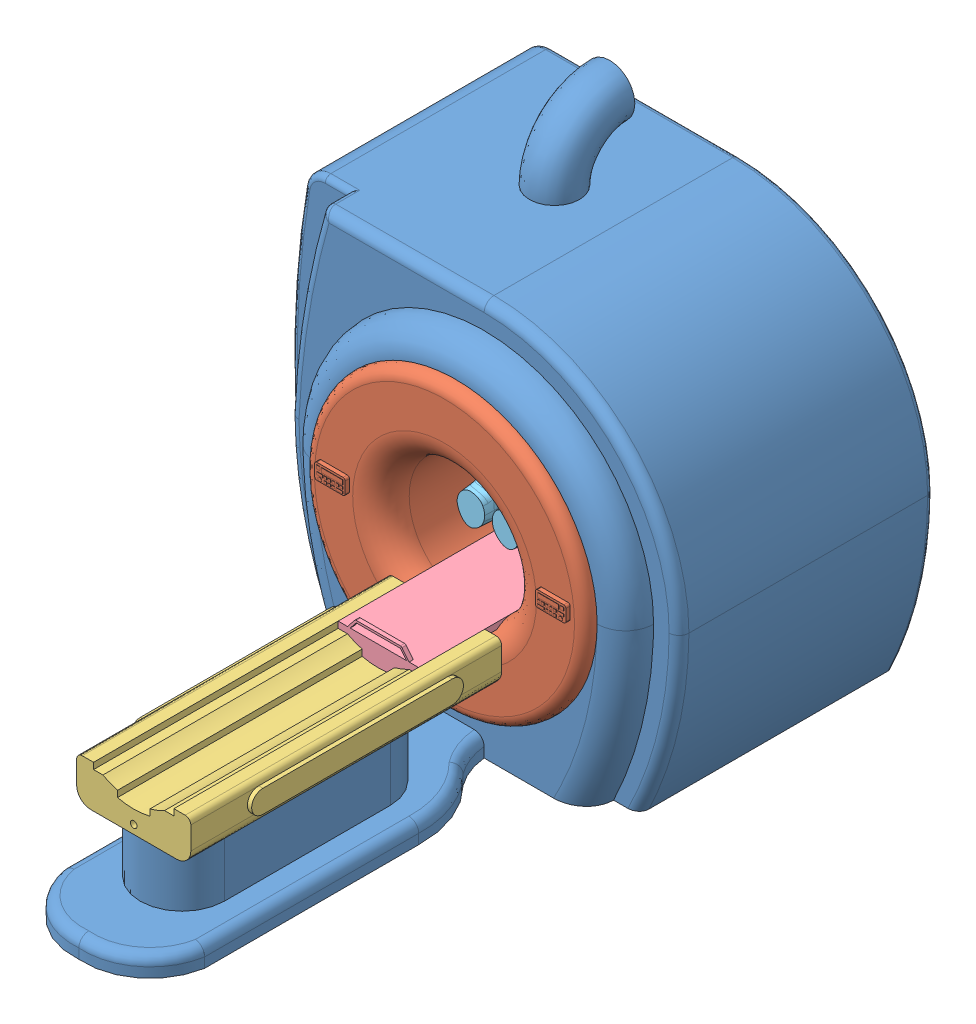
SolidWorks assembly BODYdetectorMRI, configuration Default. Lengths in mm.
Overall size (2298.25 2472.53 3646.55).
34 component instances, 9 part files, 9 mates.
Components (placement in the parent):
- MRI scanner-1: MRI scanner [Default] at (661.8458 1614.7998 1684.1916) size (2298.25 2472.53 3646.55)
  - Base Frame-1: Base Frame [Default] at (215.0742 187.8159 122.1083) size (2298.25 2472.53 3646.55)
  - Center Part-1: Center Part [Default] at (370.4063 184.7421 93.4615) size (1560 1560 1647.36)
  - Bed Base-1: Bed Base [Default] at (341.9747 -206.076 1751.6096) size (677.53 234 1716)
- Moving Bed-1: Moving Bed [Default] at (1003.8204 1488.5238 2088.1633) size (443.53 166.13 1716)
- BODYdetector3-1: BODYdetector3 [Default] at (1343.6656 1349.2154 2674.8103) x (-1 0 0) z (0 0 -1) size (637.83 509.15 817.55)
  - woman body-1: woman body [Default] at (325.4407 484.4544 221.086) size (637.83 301.02 817.55)
  - Detector1n3_3-1: Detector1n3_3 [Default] at (49.8582 665.158 553.2219) x (1 0 0) z (0 -1 0) size (495.24 340.33 231)
    - Detector1n2_changed-1: Detector1n2_changed [Default] at (214.6875 32.8122 259.0633) size (495.24 340.33 200.99)
      - top_bottomDetector2-1: top_bottomDetector2 [Default] at (5.3043 60.2155 74.3483) size (141 32 149.74)
      - CshapedDetector2-1: CshapedDetector2 [Default] at (104.3454 -76.5763 -85.899) x (0.951057 0.309017 0) z (0 0 1) size (177.89 270.84 200)
        - 1Detector-2: 1Detector [Default] at (173.0714 153.2337 184.2598) x (0.809017 0.587785 0) z (0 0 1) size (71 32 200)
        - 1Detector-4: 1Detector [Default] at (223.2683 222.3237 184.2598) x (0.309017 0.951057 0) z (0 0 1) size (71 32 200)
        - 1Detector-5: 1Detector [Default] at (223.2683 307.7237 184.2598) x (-0.309017 0.951057 0) z (0 0 1) size (71 32 200)
        - 1Detector_3modules-1: 1Detector_3modules [Default] at (91.8512 126.8436 209.2598) size (71 32 150)
        - 1Detector_3modules-2: 1Detector_3modules [Default] at (173.0714 376.8138 209.2598) x (-0.809017 0.587785 0) z (0 0 1) size (71 32 150)
      - CshapedDetector2-2: CshapedDetector2 [Default] at (-23.7368 484.2959 -85.899) x (-0.951057 -0.309017 0) z (0 0 1) size (177.89 270.84 200)
        - 1Detector-2: 1Detector [Default] at (173.0714 153.2337 184.2598) x (0.809017 0.587785 0) z (0 0 1) size (71 32 200)
        - 1Detector-4: 1Detector [Default] at (223.2683 222.3237 184.2598) x (0.309017 0.951057 0) z (0 0 1) size (71 32 200)
        - 1Detector-5: 1Detector [Default] at (223.2683 307.7237 184.2598) x (-0.309017 0.951057 0) z (0 0 1) size (71 32 200)
        - 1Detector_3modules-1: 1Detector_3modules [Default] at (91.8512 126.8436 209.2598) size (71 32 150)
        - 1Detector_3modules-2: 1Detector_3modules [Default] at (173.0714 376.8138 209.2598) x (-0.809017 0.587785 0) z (0 0 1) size (71 32 150)
      - top_bottomDetector2-2: top_bottomDetector2 [Default] at (75.3043 347.5042 74.3483) x (-1 0 0) z (0 0 1) size (141 32 149.74)
    - Detector3-1: Detector3 [Default] at (255.9219 239.5761 488.4241) x (0 -1 0) z (1 0 0) size (239.5 31 350)
  - Detector_posterial2-1: Detector_posterial2 [Default] at (218.3959 771.2045 927.1336) x (1 0 0) z (0 0 -1) size (410.4 279.65 200.24)
    - 1Detector-1: 1Detector [Default] at (83.9721 85.3161 150.6758) size (71 32 200)
    - 1Detector-2: 1Detector [Default] at (152.9721 85.3161 150.6758) size (71 32 200)
    - 1Detector-3: 1Detector [Default] at (14.9721 85.3161 150.6758) size (71 32 200)
    - 1Detector-4: 1Detector [Default] at (-66.1879 111.2254 150.6758) x (0.815027 -0.579423 0) z (0 0 1) size (71 32 200)
    - 1Detector-5: 1Detector [Default] at (234.132 111.2254 150.6758) x (0.815027 0.579423 0) z (0 0 1) size (71 32 200)
    - 1Detector_3modules-1: 1Detector_3modules [Default] at (-113.8805 184.8905 175.6758) x (0.19509 -0.980785 0) z (0 0 1) size (71 32 150)
    - 1Detector_3modules-2: 1Detector_3modules [Default] at (281.8247 184.8905 175.6758) x (0.19509 0.980785 0) z (0 0 1) size (71 32 150)
    - top_bottomDetector2-1: top_bottomDetector2 [Default] at (289.1701 259.4705 125.9183) x (0 1 0) z (0 0 1) size (141 32 149.74)
    - top_bottomDetector2-2: top_bottomDetector2 [Default] at (-121.226 329.4705 125.9183) x (0 -1 0) z (0 0 1) size (141 32 149.74)
Mates (geometry in assembly coordinates):
- Coincident1: coincident aligned: line of MRI scanner-1/Bed Base-1 through (810.4856 1491.0005 4405.104) axis (0 0 -1); line of Moving Bed-1 through (810.4856 1491.0005 3054.7931) axis (0 0 -1)
- Parallel1: parallel anti-aligned: plane of MRI scanner-1/Bed Base-1 through (810.4856 1491.0005 4405.104) normal (0 1 0); plane of Moving Bed-1 through (810.4856 1491.0005 3054.7931) normal (0 -1 0)
- Coincident4: coincident anti-aligned: plane of Moving Bed-1 through (810.4856 1525.9494 3298.5256) normal (0 1 0); plane of ? through (940.4185 1525.9494 1968.3934) normal (0 -1 0)
- Distance2: distance = 228.6 mm: line of Moving Bed-1 through (1254.0185 1525.9494 3298.5256) axis (0 0 -1); line of ? through (1025.4185 1525.9494 2043.3934) axis (0 0 -1)
- Distance3: distance = 310.8678 mm: line of ? through (1206.7786 1525.9494 1893.3934) axis (-1 0 0); line of Moving Bed-1 through (1254.0185 1525.9494 1582.5256) axis (-1 0 0)
- Parallel2: parallel aligned: line of Moving Bed-1 through (1254.0185 1525.9494 3054.7931) axis (0 0 -1); line of BODYdetector3-1/Detector1n3_3-1/Detector3-1 through (1212.8855 1530.9494 1992.0123) axis (0 0 -1)
- Coincident6: coincident anti-aligned: plane of Moving Bed-1 through (810.4856 1525.9494 3054.7931) normal (0 1 0); plane of BODYdetector3-1/Detector1n3_3-1/Detector3-1 through (1037.8855 1525.9494 1882.0123) normal (0 -1 0)
- Distance4: distance = 41.1329 mm aligned: plane of BODYdetector3-1/Detector1n3_3-1/Detector3-1 through (1212.8855 1530.9494 1772.0123) normal (1 0 0); plane of Moving Bed-1 through (1254.0185 1525.9494 3054.7931) normal (1 0 0)
- Distance5: distance = 433.2191 mm aligned: plane of BODYdetector3-1/Detector1n3_3-1/Detector3-1 through (862.8855 1530.9494 1772.0123) normal (0 0 -1); plane of Moving Bed-1 through (1032.252 1798.0168 1338.7931) normal (0 0 -1)
